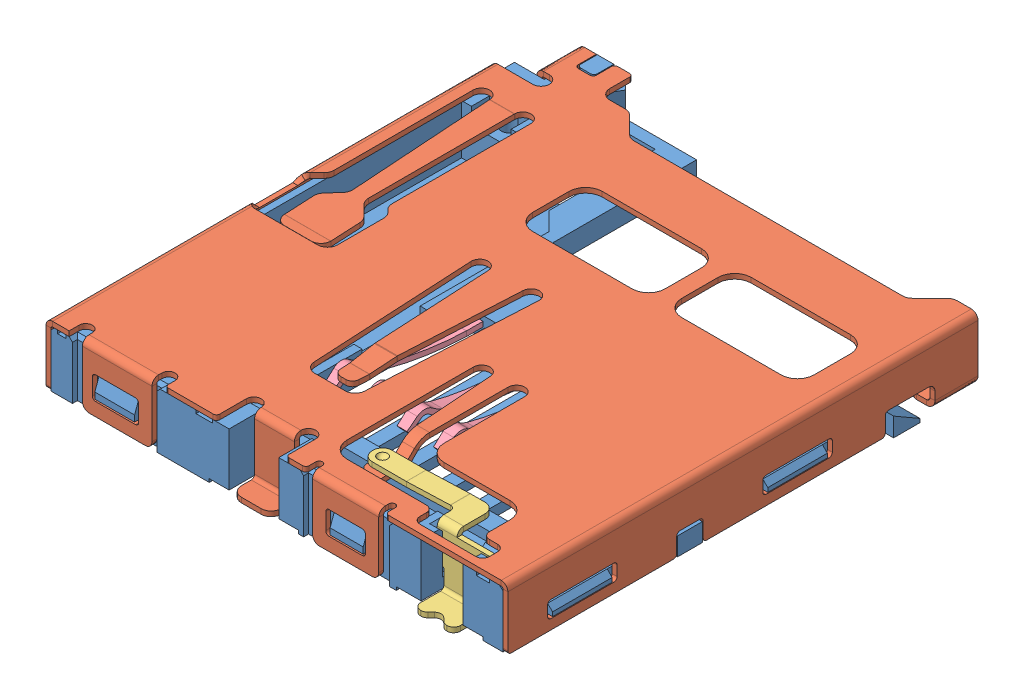
SolidWorks assembly microSD_Connector, configuration Default. Lengths in mm.
Overall size (14.1 1.9 15.45).
12 component instances, 5 part files, 11 mates.
Components (placement in the parent):
- microSD_Body-1: microSD_Body [Default] at origin size (14.1 1.85 15.2)
- microSD_Cover-1: microSD_Cover [Default] at (0 1.7 0) x (1 0 0) z (0 0 -1) size (13.95 1.9 15.2)
- microSD_Card_Detect-1: microSD_Card_Detect [Default] at (4.99 -0.05 7.4) size (4.45 1.9 2.05)
- microSD_Spring-2: microSD_Spring [Default] at (-3.85 1.125 6.9) x (-0.521999 -0.852946 0) z (0.852946 -0.521999 0) size (1.41 10.35 1.43) (hidden)
- microSD_Pin-1: microSD_Pin [11.15] at (5.725 -0.05 -2) x (0 0 1) z (-1 0 0) size (7.25 1.15 0.6)
- microSD_Pin-2: microSD_Pin [11.15] at (4.625 -0.05 -2) x (0 0 1) z (-1 0 0) size (7.25 1.15 0.6)
- microSD_Pin-3: microSD_Pin [11.35] at (3.525 -0.05 -2) x (0 0 1) z (-1 0 0) size (7.25 1.15 0.6)
- microSD_Pin-4: microSD_Pin [11.15] at (2.425 -0.05 -2) x (0 0 1) z (-1 0 0) size (7.25 1.15 0.6)
- microSD_Pin-5: microSD_Pin [11.35] at (1.325 -0.05 -2) x (0 0 1) z (-1 0 0) size (7.25 1.15 0.6)
- microSD_Pin-6: microSD_Pin [11.15] at (0.225 -0.05 -2) x (0 0 1) z (-1 0 0) size (7.25 1.15 0.6)
- microSD_Pin-7: microSD_Pin [10.75] at (-0.875 -0.05 -2) x (0 0 1) z (-1 0 0) size (7.25 1.15 0.6)
- microSD_Pin-8: microSD_Pin [11.15] at (-1.975 -0.05 -2) x (0 0 1) z (-1 0 0) size (7.25 1.15 0.6)
Mates (geometry in assembly coordinates):
- Coincident3: coincident: plane of microSD_Body-1 through (0 1.7 0) normal (0 1 0); plane of microSD_Cover-1 through (0 1.7 0) normal (0 -1 0)
- Coincident9: coincident: plane of microSD_Body-1 through (5.625 -0.001 6.8) normal (0 0 1); plane of microSD_Card_Detect-1 through (4.99 -0.05 6.8) normal (0 0 -1)
- Width5: width: plane of microSD_Body-1 through (4.355 -0.001 6.8) normal (1 0 0); plane of microSD_Body-1 through (5.625 -0.001 8.8) normal (-1 0 0); plane of microSD_Card_Detect-1 through (4.39 0.1 6.95) normal (-1 0 0); plane of microSD_Card_Detect-1 through (5.59 0.1 6.95) normal (1 0 0)
- Width6: width: plane of microSD_Body-1 through (-6.825 1.7 -7.6) normal (-1 0 0); plane of microSD_Body-1 through (6.825 1.7 -7.6) normal (1 0 0); plane of microSD_Cover-1 through (6.825 1.7 0) normal (-1 0 0); plane of microSD_Cover-1 through (-6.825 1.7 0) normal (1 0 0)
- Coincident11: coincident: plane of microSD_Body-1 through (0 0 7.45) normal (0 0 1); plane of microSD_Cover-1 through (0 1.7 7.45) normal (0 0 -1)
- Coincident12: coincident: plane of microSD_Cover-1 through (0 1.85 0) normal (0 1 0); plane of microSD_Card_Detect-1 through (4.99 1.85 7.4) normal (0 1 0)
- Coincident13: coincident: plane of microSD_Body-1 through (-4.725 -0.001 7) normal (0 0 -1); plane of microSD_Spring-2 through (-3.85 1.125 7) normal (0 0 -1)
- Concentric1: concentric: cylinder of microSD_Body-1 through (-3.85 1.125 5.5) axis (0 0 1) radius 0.275; point of microSD_Spring-2
- Coincident14: coincident: point of microSD_Body-1; point of microSD_Pin-1
- Coincident15: coincident: point of microSD_Body-1; point of microSD_Pin-1
- Coincident16: coincident: plane of microSD_Body-1 through (5.425 0.3 -7.601) normal (0 1 0); plane of microSD_Pin-1 through (5.425 0.3 -0.3) normal (0 -1 0)
